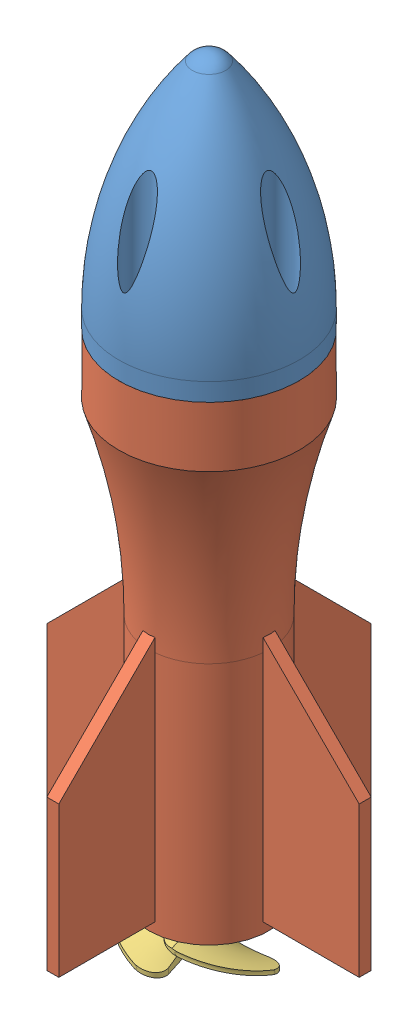
SolidWorks assembly MS-A-0012-Torpedo, configuration Default. Lengths in mm.
Overall size (65.99 166.17 65.99).
3 component instances, 3 part files, 0 mates.
Components (placement in the parent):
- MS-P-0041-AltNoseCone-1: MS-P-0041-AltNoseCone [Default] at (11.1866 4.6011 24.4761) size (38.1 62.23 38.1)
- MS-P-0042-Torpedo_Body-1: MS-P-0042-Torpedo_Body [Default] at (11.1866 -96.9989 24.4761) x (0 0 1) z (0 1 0) size (65.99 65.99 103.87)
- MS-P-001-SpiralProppeler-SelfMade-1: MS-P-001-SpiralProppeler-SelfMade [Default] at (11.1866 -99.3387 24.4761) x (0.953749 0 -0.300604) z (0 -1 0) size (29.55 29.55 11.64)
